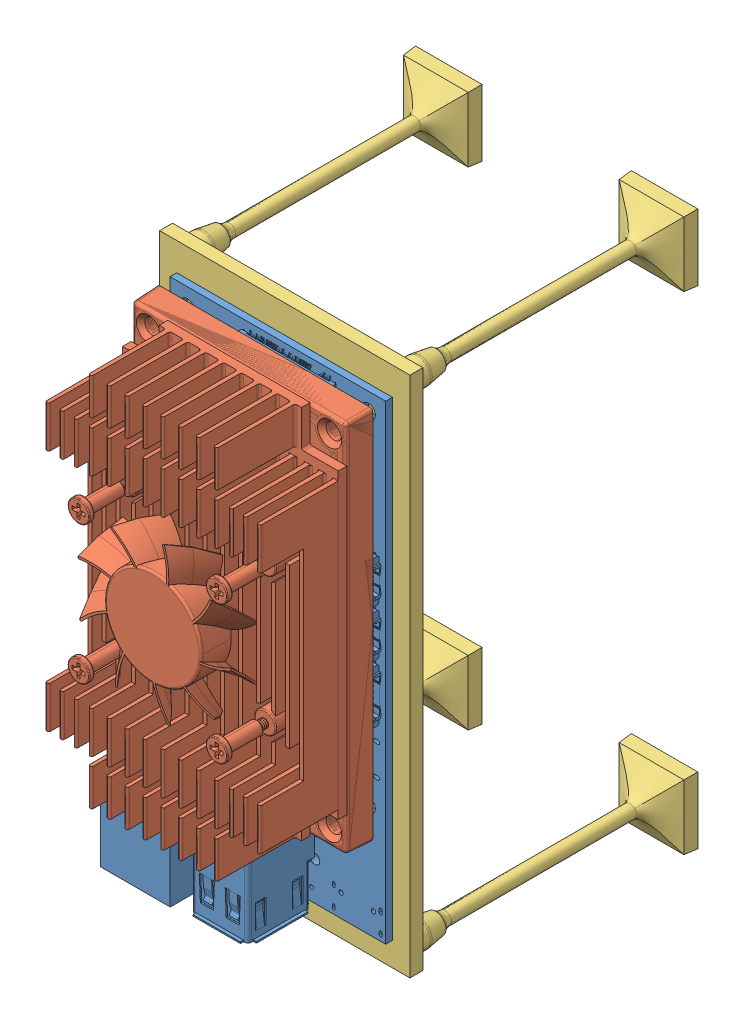
SolidWorks assembly PC, configuration Default. Lengths in mm.
Overall size (65.42 128.42 94.81).
3 component instances, 3 part files, 3 mates.
Components (placement in the parent):
- AUV-1: AUV [Default] at (-224.6477 -98.1963 82.9375) size (50 109.5 20.4)
- TX2-1: TX2 [Default] at (-86.6477 -94.1963 84.7735) x (0 1 0) z (0 0 1) size (87.02 50.02 28.44)
- Parte2^PC-1: Parte2^PC [Default] at (8.237 8.1582 81.3693) x (-1 0 0) z (0 0 -1) size (65.42 128.42 63) (virtual)
Mates (geometry in assembly coordinates):
- Distanza2: distance = 3 mm: plane of AUV-1 through (-82.6477 -120.1963 82.9375) normal (0 0 1); plane of TX2-1 through (-82.6477 -98.1963 85.9375) normal (0 0 -1)
- Concentrico1: concentric: cylinder of AUV-1 through (-128.6477 -94.1963 81.3693) axis (0 0 -1) radius 1.6; cone of TX2-1 through (-128.6477 -94.1963 91.9375) axis (0 0 -1)
- Coincidente1: coincident: point of Parte2^PC-1; point of assembly
